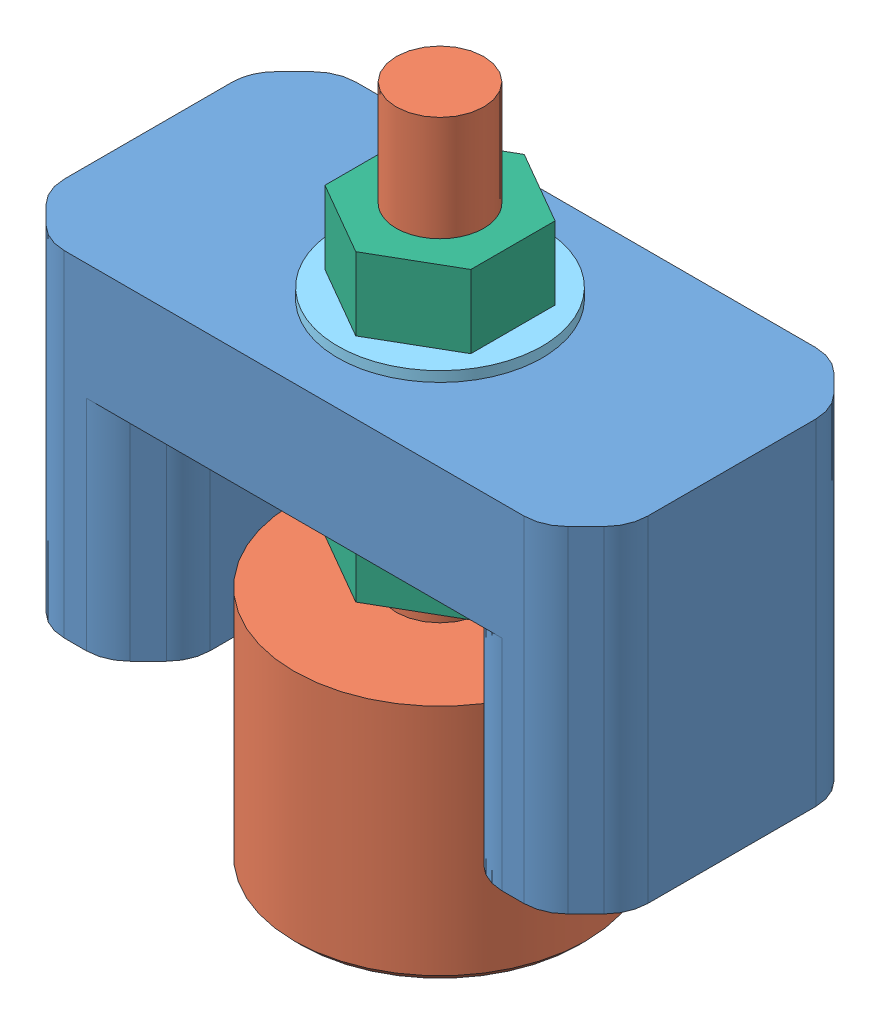
SolidWorks assembly Assemblage Roue Porteuse, configuration Défaut. Lengths in mm.
Overall size (40 50.71 20).
11 component instances, 6 part files, 19 mates.
Components (placement in the parent):
- Support Bille porteuse-1: Support Bille porteuse [Défaut] at (1.9744 -30.0894 -26.9817) size (40 23 20)
- Bille porteuse ALWAYE D12_7-2: Bille porteuse ALWAYE D12_7 [Défaut] at (1.9744 -30.1894 -26.9817) size (20 46.5 20)
- Bille D12-2: Bille D12 [Défaut] at (1.9744 -38.8998 -26.9817) size (12 12 12)
- Insert M4-2: Insert M4 [Défaut] at (16.9744 -30.0894 -26.9817) x (-0.837169 0 -0.546944) z (0 1 0) size (7 7 8)
- Insert M4-3: Insert M4 [Défaut] at (-13.0256 -30.0894 -26.9817) x (-0.837169 0 -0.546944) z (0 1 0) size (7 7 8)
- Rondelle M6-6: Rondelle M6 [Défaut] at (1.9744 -17.1894 -26.9817) x (1 0 0) z (0 1 0) size (14 14 0.7)
- Rondelle M6-7: Rondelle M6 [Défaut] at (1.9744 -16.4894 -26.9817) x (1 0 0) z (0 1 0) size (14 14 0.7)
- Rondelle M6-5: Rondelle M6 [Défaut] at (1.9744 -15.7894 -26.9817) x (1 0 0) z (0 1 0) size (14 14 0.7)
- Rondelle M6-4: Rondelle M6 [Défaut] at (1.9744 -7.0894 -26.9817) x (1 0 0) z (0 1 0) size (14 14 0.7)
- Ecrou M6-4: Ecrou M6 [Défaut] at (1.9744 -6.3894 -26.9817) size (10 5 11.55)
- Ecrou M6-5: Ecrou M6 [Défaut] at (1.9744 -22.1894 -26.9817) size (10 5 11.55)
Mates (geometry in assembly coordinates):
- Coaxiale9: concentric: cylinder of Bille porteuse ALWAYE D12_7-2 through (1.9744 -40.1894 -26.9817) axis (0 1 0) radius 6.75; sphere of Bille D12-2
- Verrouiller1: lock: unknown of Bille porteuse ALWAYE D12_7-2; unknown of Bille D12-2
- Coaxiale11: concentric anti-aligned: cylinder of Support Bille porteuse-1 through (1.9744 -17.0894 -26.9817) axis (0 1 0) radius 3.2; cylinder of Bille porteuse ALWAYE D12_7-2 through (1.9744 5.8106 -26.9817) axis (0 -1 0) radius 3
- Coaxiale13: concentric aligned: cylinder of Support Bille porteuse-1 through (-13.0256 -23.0894 -26.9817) axis (0 -1 0) radius 2.75; cylinder of Insert M4-3 through (-13.0256 -22.0894 -26.9817) axis (0 -1 0) radius 2.75
- Coaxiale14: concentric aligned: cylinder of Support Bille porteuse-1 through (16.9744 -23.0894 -26.9817) axis (0 -1 0) radius 2.75; cylinder of Insert M4-2 through (16.9744 -22.0894 -26.9817) axis (0 -1 0) radius 2.75
- Coïncidente4: coincident anti-aligned: plane of Support Bille porteuse-1 through (1.9744 -29.0894 -26.9817) normal (0 -1 0); plane of Insert M4-2 through (16.9744 -29.0894 -26.9817) normal (0 1 0)
- Coïncidente5: coincident anti-aligned: plane of Support Bille porteuse-1 through (1.9744 -29.0894 -26.9817) normal (0 -1 0); plane of Insert M4-3 through (-13.0256 -29.0894 -26.9817) normal (0 1 0)
- Coïncidente6: coincident anti-aligned: plane of Rondelle M6-7 through (1.9744 -15.7894 -26.9817) normal (0 1 0); plane of Rondelle M6-5 through (1.9744 -15.7894 -26.9817) normal (0 -1 0)
- Coïncidente7: coincident anti-aligned: plane of Rondelle M6-6 through (1.9744 -16.4894 -26.9817) normal (0 1 0); plane of Rondelle M6-7 through (1.9744 -16.4894 -26.9817) normal (0 -1 0)
- Coaxiale15: concentric aligned: cylinder of Rondelle M6-6 through (1.9744 -17.9894 -26.9817) axis (0 1 0) radius 3; cylinder of Rondelle M6-7 through (1.9744 -17.2894 -26.9817) axis (0 1 0) radius 3
- Coaxiale16: concentric aligned: cylinder of Rondelle M6-7 through (1.9744 -17.2894 -26.9817) axis (0 1 0) radius 3; cylinder of Rondelle M6-5 through (1.9744 -16.5894 -26.9817) axis (0 1 0) radius 3
- Coaxiale17: concentric anti-aligned: cylinder of Bille porteuse ALWAYE D12_7-2 through (1.9744 5.8106 -26.9817) axis (0 -1 0) radius 3; cylinder of Rondelle M6-7 through (1.9744 -17.2894 -26.9817) axis (0 1 0) radius 3
- Coïncidente9: coincident anti-aligned: plane of Support Bille porteuse-1 through (1.9744 -15.0894 -26.9817) normal (0 -1 0); plane of Rondelle M6-5 through (1.9744 -15.0894 -26.9817) normal (0 1 0)
- Coïncidente11: coincident anti-aligned: plane of Support Bille porteuse-1 through (1.9744 -7.0894 -26.9817) normal (0 1 0); plane of Rondelle M6-4 through (1.9744 -7.0894 -26.9817) normal (0 -1 0)
- Coaxiale18: concentric anti-aligned: cylinder of Bille porteuse ALWAYE D12_7-2 through (1.9744 5.8106 -26.9817) axis (0 -1 0) radius 3; cylinder of Rondelle M6-4 through (1.9744 -7.8894 -26.9817) axis (0 1 0) radius 3
- Coaxiale19: concentric aligned: cylinder of Bille porteuse ALWAYE D12_7-2 through (1.9744 5.8106 -26.9817) axis (0 -1 0) radius 3; cylinder of Ecrou M6-4 through (1.9744 -1.3894 -26.9817) axis (0 -1 0) radius 3
- Coaxiale20: concentric aligned: cylinder of Bille porteuse ALWAYE D12_7-2 through (1.9744 5.8106 -26.9817) axis (0 -1 0) radius 3; cylinder of Ecrou M6-5 through (1.9744 -17.1894 -26.9817) axis (0 -1 0) radius 3
- Coïncidente12: coincident: plane of Rondelle M6-6 through (1.9744 -17.1894 -26.9817) normal (0 -1 0); line of Ecrou M6-5 through (-3.0256 -17.1894 -29.8684) axis (0 0 1)
- Coïncidente13: coincident anti-aligned: plane of Rondelle M6-4 through (1.9744 -6.3894 -26.9817) normal (0 1 0); plane of Ecrou M6-4 through (1.9744 -6.3894 -26.9817) normal (0 -1 0)
